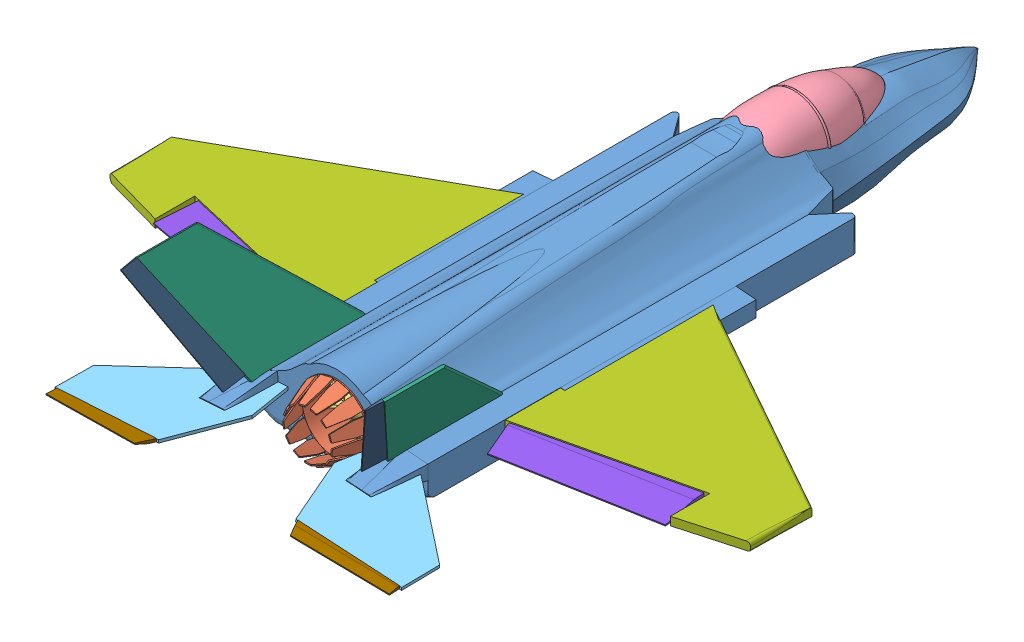
SolidWorks assembly Assem, configuration Default. Lengths in mm.
Overall size (887.31 280.13 1063.88).
16 component instances, 10 part files, 16 mates.
Components (placement in the parent):
- body-1: body [Default] at (-321.1551 -593.2912 224.1362) size (309.35 188.95 959.56)
- engine shell-1: engine shell [Default] at (18.105 35.9025 502.7209) x (0 -1 0) z (0 0 1) size (96.83 97.54 358.3)
- engine-1: engine [Default] at (18.105 35.9025 482.9622) x (0.240543 -0.970638 0) z (0 0 1) size (91.44 91.36 286.77)
- window-1: window [Default] at (-316.2164 -36.1175 -2081.926) size (113.56 89.29 207.78)
- wing 1-1: wing 1 [Default] at (-377.6905 69.7884 -135.5455) x (0.983029 -0.069486 0.169784) z (0.070509 0.997511 0) size (196.31 153.37 3.81)
- wing 1-2: wing 1 [Default] at (413.6319 73.589 -135.5455) x (-0.983029 -0.069486 0.169784) z (0.070509 -0.997511 0) size (196.31 153.37 3.81)
- wing 2-1: wing 2 [Default] at (-87.4678 71.7563 -131.013) x (-0.454707 0.890641 0) z (-0.890641 -0.454707 0) size (177.63 239.58 3.81)
- wing 2-2: wing 2 [Default] at (127.0712 70.0239 -131.013) x (0.454707 0.890641 0) z (-0.890641 0.454707 0) size (177.63 239.58 3.81)
- wing 3-1: wing 3 [Default] at (661.1205 33.0381 -39.2367) x (0 1 0) z (0 0 1) size (11.87 324.83 293.42)
- wing 3s-1: wing 3s [Default] at (15.8585 42.8453 -51.1008) size (223.38 8.89 98.83)
- wing 3s-2: wing 3s [Default] at (20.3515 33.9553 -51.1008) x (-1 0 0) z (0 0 1) size (223.38 8.89 98.83)
- wing 3-2: wing 3 [Default] at (-624.9104 44.5931 -39.2367) x (0 -1 0) z (0 0 1) size (11.87 324.83 293.42)
- wing 1s-1: wing 1s [Default] at (-39.1544 46.161 -54.4523) x (0.995998 -0.070402 -0.055053) z (0.054916 -0.003882 0.998483) size (139.44 3.81 20.87)
- wing 1s-2: wing 1s [Default] at (75.0959 49.9615 -54.4523) x (-0.995998 -0.070402 -0.055053) z (-0.054916 -0.003882 0.998483) size (139.44 3.81 20.87)
- wing 2s-1: wing 2s [Default] at (-153.3388 193.7285 1062.5636) x (-0.068069 0.133327 -0.988732) z (0.449583 -0.880605 -0.149698) size (74.55 3.81 169.92)
- wing 2s-2: wing 2s [Default] at (186.1555 195.461 1062.5636) x (0.068069 0.133327 -0.988732) z (-0.449583 -0.880605 -0.149698) size (74.55 3.81 169.92)
Mates (geometry in assembly coordinates):
- Concentric1: concentric anti-aligned: cylinder of body-1 through (18.105 35.9025 500.7422) axis (0 0 1) radius 48.26; cylinder of engine shell-1 through (18.105 35.9025 830.3809) axis (0 0 -1) radius 48.26
- Parallel1: parallel aligned: line of engine shell-1 through (-27.5238 33.0163 663.4195) axis (1 0 0); line of body-1 through (-45.3886 -25.7536 224.1362) axis (1 0 0)
- Coincident4: coincident anti-aligned: plane of body-1 through (31.816 -55.1857 828.6562) normal (0 0 1); plane of engine shell-1 through (-15.3445 1.8023 828.6562) normal (0 0 -1)
- Concentric2: concentric aligned: cylinder of engine shell-1 through (18.105 35.9025 830.3809) axis (0 0 -1) radius 45.72; cylinder of engine-1 through (18.105 35.9025 810.6222) axis (0 0 -1) radius 5.08
- Distance1: distance = 25.4 mm anti-aligned: plane of engine-1 through (18.105 35.9025 526.1422) normal (0 0 -1); plane of body-1 through (18.105 35.9025 500.7422) normal (0 0 1)
- Parallel4: parallel aligned: line of body-1 through (-108.5328 1.3154 818.4962) axis (0 0 -1); line of window-1 through (46 41.277 260.6491) axis (0 0 -1)
- Parallel5: parallel aligned: plane of body-1 through (283.3649 -35.2199 358.5717) normal (0 -1 0); plane of window-1 through (-316.2164 41.277 -2081.926) normal (0 -1 0)
- Parallel6: parallel aligned: plane of body-1 through (172.7789 42.9216 645.0142) normal (0.070509 0.997511 0); plane of wing 1^Assem-1 through (-377.4219 73.589 -135.5455) normal (0.070509 0.997511 0)
- Lock1: lock: unknown of body-1; unknown of wing 1-1
- Parallel7: parallel anti-aligned: line of body-1 through (-75.4461 47.6097 828.6562) axis (0 0 -1); line of wing 2-1 through (-70.7824 39.0744 695.2769) axis (0 0 1)
- Lock2: lock: unknown of body-1; unknown of wing 2-1
- Lock5: lock: unknown of body-1; unknown of window-1
- Lock6: lock: unknown of body-1; unknown of wing 3-1
- Lock7: lock: unknown of wing 3-1; unknown of wing 3s-1
- Lock8: lock: unknown of wing 1-1; unknown of wing 1s-1
- Lock9: lock: unknown of wing 2-1; unknown of wing 2s-1
